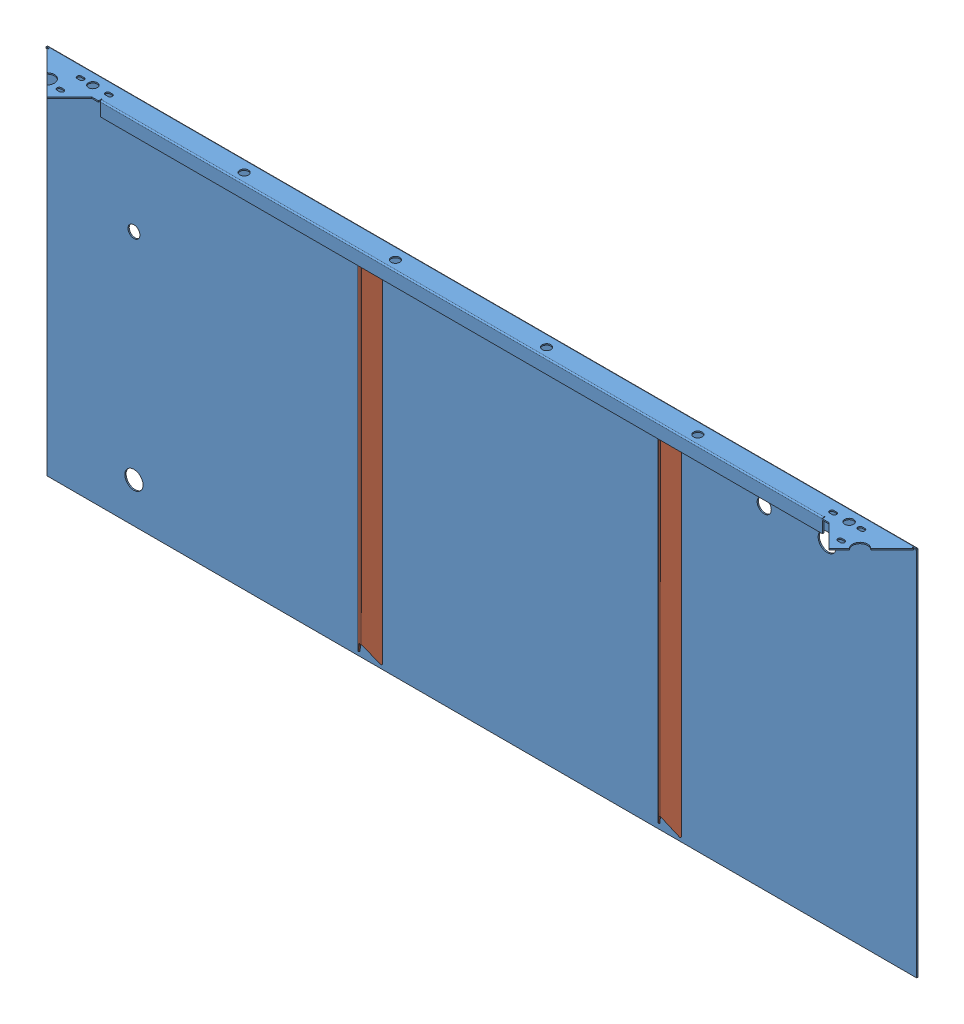
SolidWorks assembly 組合件3, configuration 預設. Lengths in mm.
Overall size (1380 590.4 88.78).
3 component instances, 2 part files, 7 mates.
Components (placement in the parent):
- LB-A54A-02-18-1: LB-A54A-02-18 [預設] at (-93858.9243 24292.5646 -35.896) size (1380 590.4 71.79)
- LB-A54A-02-36-1: LB-A54A-02-36 [預設] at (15806.0084 -101259.211 -18772.2864) x (0 1 0) z (-0.760138 0 -0.649762) size (580.6 25.51 29.5)
- LB-A54A-02-36-2: LB-A54A-02-36 [預設] at (17292.2336 -101259.212 -17857.7208) x (0 1 0) z (-0.723044 0 -0.690802) size (580.6 25.51 29.5)
Mates (geometry in assembly coordinates):
- 重合/共線/共點1: coincident anti-aligned: plane of LB-A54A-02-18-1 through (588.8436 343.6572 -33.896) normal (0 0 1); line of LB-A54A-02-36-1
- 重合/共線/共點2: coincident: plane of LB-A54A-02-18-1 through (588.8436 343.6572 -33.896) normal (0 0 1); line of LB-A54A-02-36-1
- 重合/共線/共點3: coincident: line of LB-A54A-02-18-1; plane of LB-A54A-02-36-1 through (-247.7547 293.6704 -29.1269) normal (-0.649762 0 0.760138)
- 重合/共線/共點4: coincident anti-aligned: plane of LB-A54A-02-18-1 through (588.8436 298.6704 11.0828) normal (0 -1 0); plane of LB-A54A-02-36-1 through (-230.3328 298.6704 -14.8925) normal (0 1 0)
- 重合/共線/共點5: coincident: line of LB-A54A-02-18-1; line of ?
- 重合/共線/共點6: coincident: plane of LB-A54A-02-18-1 through (588.8436 343.6572 -33.896) normal (0 0 1); line of ?
- 重合/共線/共點8: coincident: line of LB-A54A-02-18-1; plane of ? through (243.1681 189.6659 -15.8199) normal (0 1 0)
